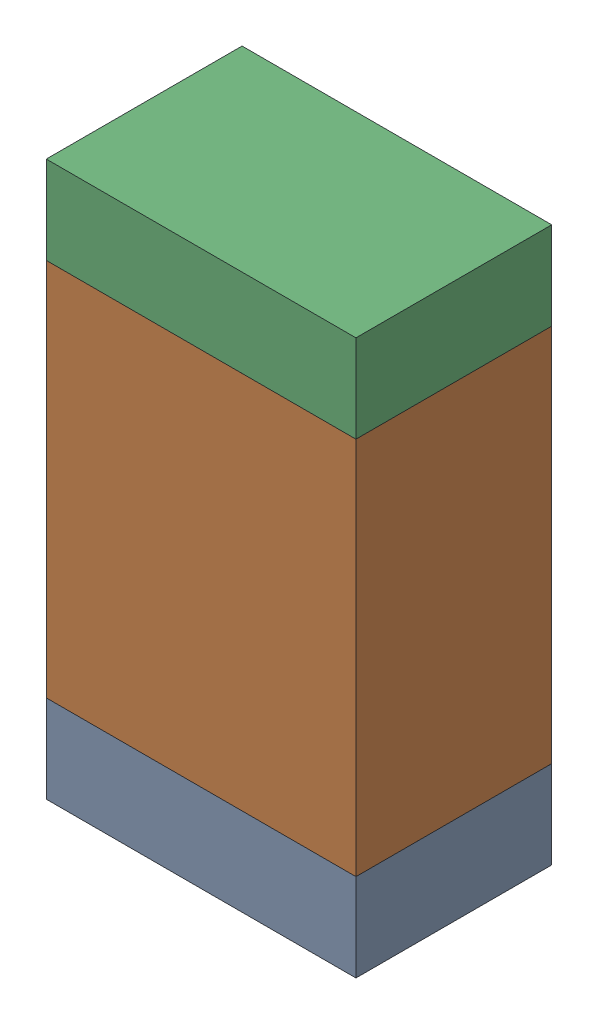
SolidWorks assembly R5-1, configuration Default. Lengths in mm.
Overall size (0.95 1.7 0.6).
6 component instances, 2 part files, 0 mates.
Components (placement in the parent):
- 959206216-1-1: 959206216-1 [Default] at (120.9041 81.6699 0) size (0.95 0.27 0.6)
  - Extruded-31-1: Extruded-31 [Default] at origin size (0.95 0.27 0.6)
- 959206352-1-1: 959206352-1 [Default] at (120.9041 82.3849 0) size (0.95 1.16 0.6)
  - Extruded-32-1: Extruded-32 [Default] at origin size (0.95 1.16 0.6)
- 959206216-1-2: 959206216-1 [Default] at (120.9041 83.0999 0) size (0.95 0.27 0.6)
  - Extruded-31-1: Extruded-31 [Default] at origin size (0.95 0.27 0.6)
